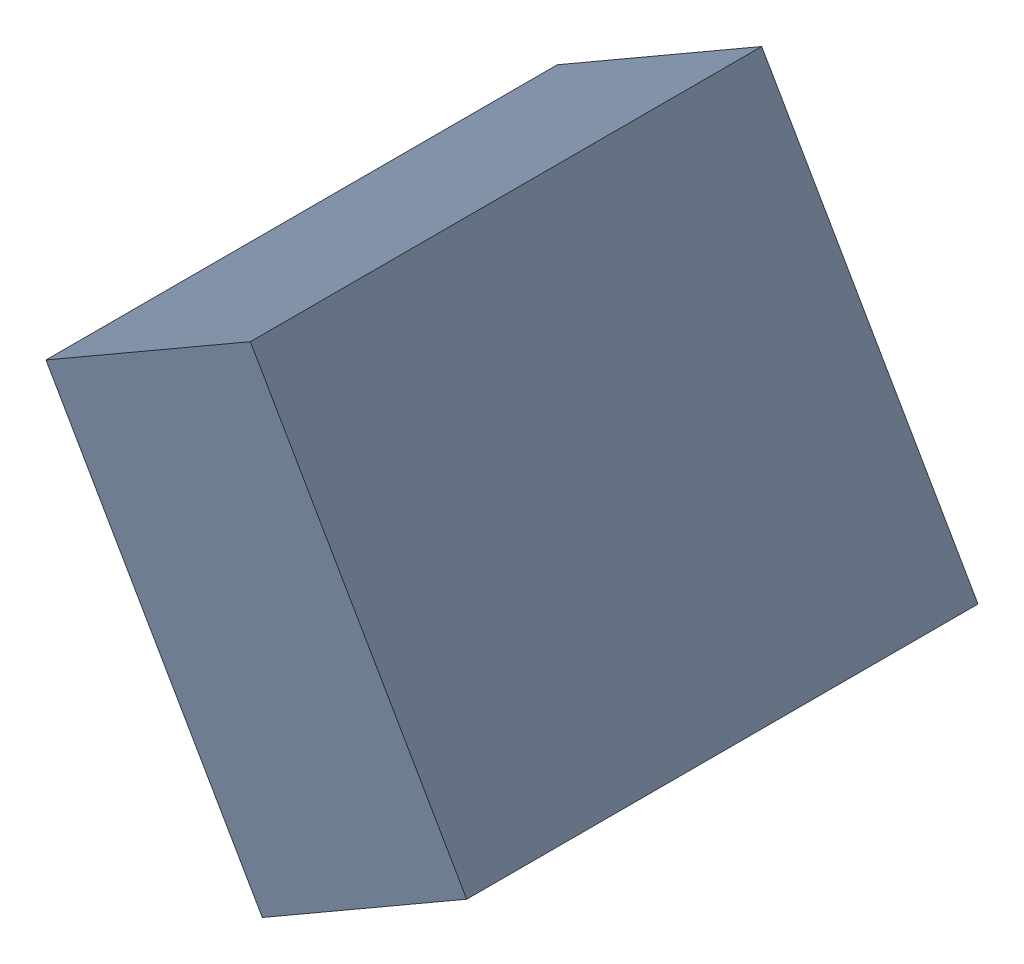
SolidWorks assembly C28_TDA5, configuration Standard. Lengths in mm.
Overall size (1.07 1.25 1.3).
2 component instances, 1 part files, 0 mates.
Components (placement in the parent):
- 885543192-1: 885543192 [Standard] at (-47.9677 -31.0933 0) size (1.07 1.25 1.3)
  - Extruded_27-1: Extruded_27 [Standard] at origin size (1.07 1.25 1.3)
